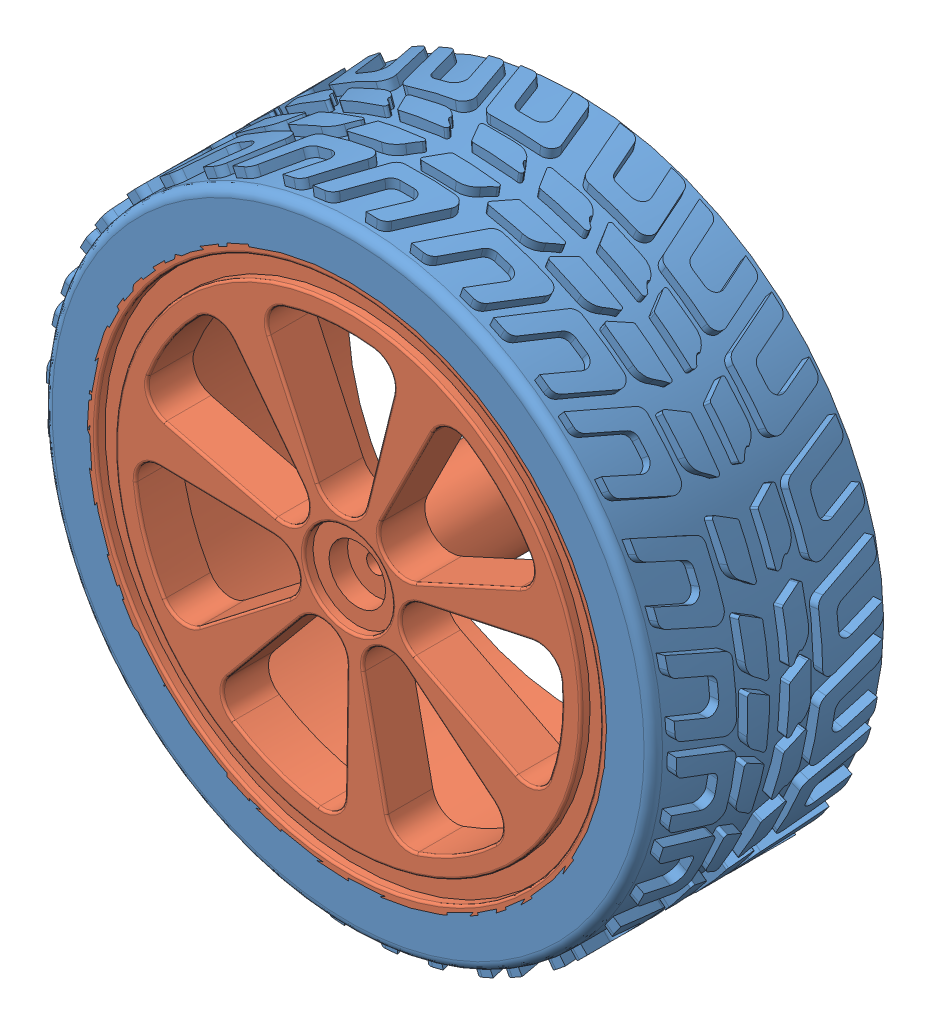
SolidWorks assembly wheel assemble, configuration Default. Lengths in mm.
Overall size (68 68 25).
2 component instances, 2 part files, 0 mates.
Components (placement in the parent):
- Tire-1-1: Tire-1 [Default] at origin size (68 68 24.89)
- WheelFrame-2-1: WheelFrame-2 [Default] at (-797.8323 -276.5666 -0.108) size (56.38 56.38 25)
